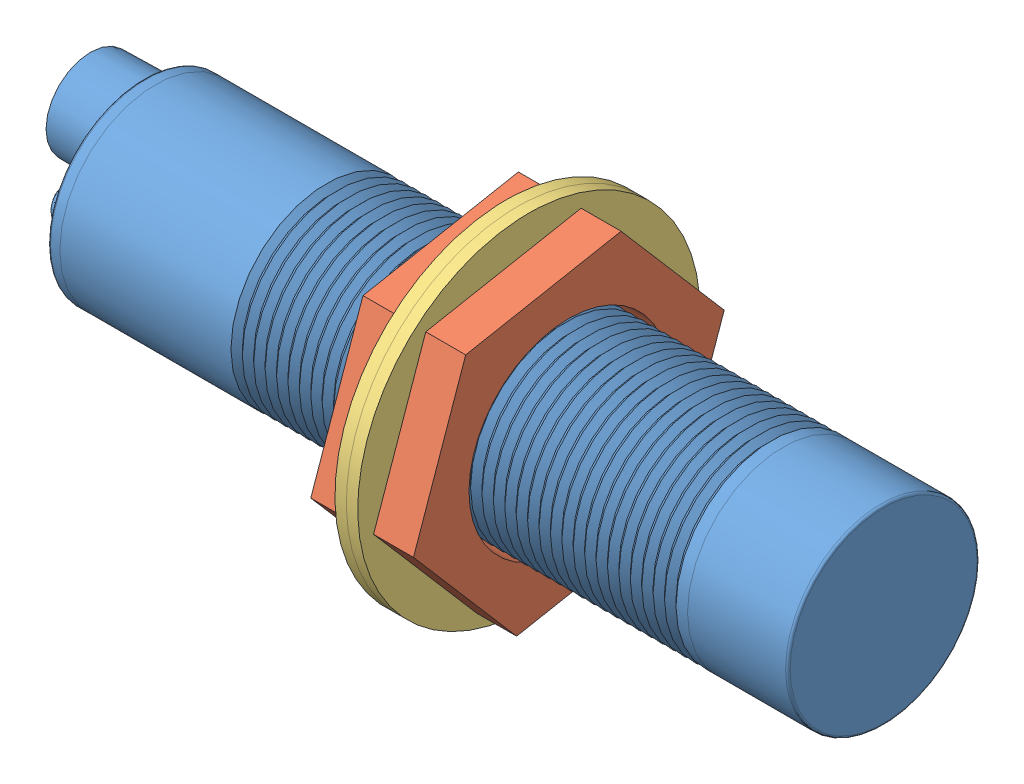
SolidWorks assembly Inductive Proximity Sensor, configuration Default. Lengths in mm.
Overall size (73.6 36.66 36.27).
5 component instances, 3 part files, 9 mates.
Components (placement in the parent):
- Sensor Body-1: Sensor Body [Default] at (-6.2225 39.7633 58.5792) size (73.6 17.21 17.21)
- Nut-1: Nut [Default] at (25.4974 39.7633 58.5792) x (0 0.757948 0.652315) z (0 -0.652315 0.757948) size (27.71 3.5 24)
- Nut-2: Nut [Default] at (30.9974 39.7633 58.5792) x (0 0.757948 0.652315) z (0 -0.652315 0.757948) size (27.71 3.5 24)
- Washer-1: Washer [Default] at (26.4974 39.7633 58.5792) x (0 0 -1) z (0 1 0) size (30 1 30)
- Washer-2: Washer [Default] at (27.4974 39.7633 58.5792) x (0 0 -1) z (0 1 0) size (30 1 30)
Mates (geometry in assembly coordinates):
- Concentric1: concentric: cylinder of Sensor Body-1 through (58.5775 39.7633 58.5792) axis (-1 0 0) radius 8.39; cylinder of Nut-1 through (21.9974 39.7633 58.5792) axis (1 0 0) radius 8.75
- Concentric2: concentric: cylinder of Sensor Body-1 through (49.7775 39.7633 58.5792) axis (-1 0 0) radius 8.395; cylinder of Washer-2 through (26.4974 39.7633 58.5792) axis (1 0 0) radius 15
- Concentric3: concentric: cylinder of Sensor Body-1 through (49.7775 39.7633 58.5792) axis (-1 0 0) radius 8.395; cylinder of Washer-1 through (25.4974 39.7633 58.5792) axis (1 0 0) radius 15
- Concentric4: concentric: cylinder of Sensor Body-1 through (49.7775 39.7633 58.5792) axis (-1 0 0) radius 8.395; cylinder of Nut-2 through (27.4974 39.7633 58.5792) axis (1 0 0) radius 8.75
- Coincident1: coincident: plane of Nut-2 through (27.4974 39.7633 58.5792) normal (-1 0 0); plane of Washer-2 through (27.4974 39.7633 58.5792) normal (1 0 0)
- Coincident2: coincident: plane of Washer-1 through (26.4974 39.7633 58.5792) normal (1 0 0); plane of Washer-2 through (26.4974 39.7633 58.5792) normal (-1 0 0)
- Coincident3: coincident: plane of Nut-1 through (25.4974 39.7633 58.5792) normal (1 0 0); plane of Washer-1 through (25.4974 39.7633 58.5792) normal (-1 0 0)
- Coincident4: coincident: plane of Nut-1 through (21.9974 26.6843 63.1552) normal (0 -0.652315 0.757948); plane of Nut-2 through (27.4974 26.6843 63.1552) normal (0 -0.652315 0.757948)
- Screw1: screw = 1: cylinder of Sensor Body-1 through (58.5775 39.7633 58.5792) axis (-1 0 0) radius 8.39; cylinder of Nut-2 through (27.4974 39.7633 58.5792) axis (1 0 0) radius 8.75
